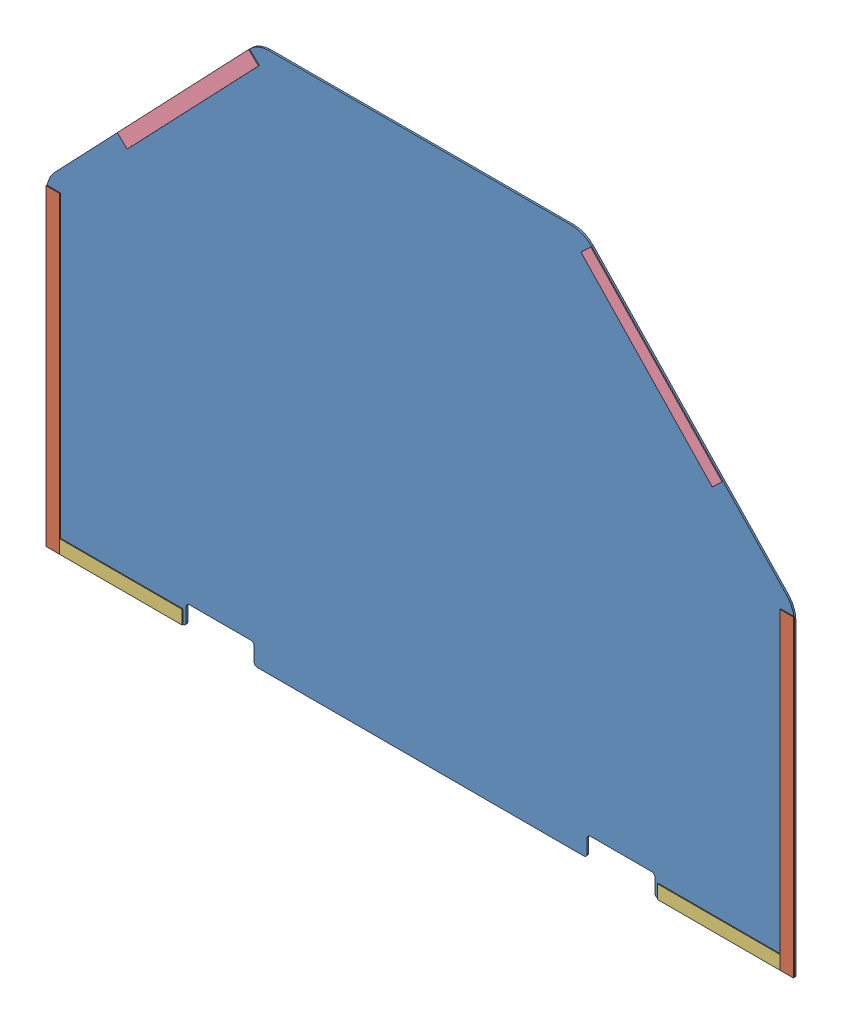
SolidWorks assembly GE-19081, configuration GE-19081-red. Lengths in mm.
Overall size (1397 1009.65 4.76).
7 component instances, 4 part files, 9 mates.
Components (placement in the parent):
- GE-19081-1: GE-19081 [GE-19081] at origin
- Loop_1_23-1: Loop_1_23 [Default] at (-685.8 292.1 4.7625) x (0 -1 0) z (0 0 -1)
- Loop_1_9-1: Loop_1_9 [Default] at (-673.1 0 3.175) x (1 0 0) z (0 -1 0)
- Loop_1_23-2: Loop_1_23 [Default] at (685.8 292.1 3.175) x (0 -1 0) z (0 0 1)
- Loop_1_9-2: Loop_1_9 [Default] at (673.1 25.4 3.175) x (-1 0 0) z (0 1 0)
- Loop_1_14-2: Loop_1_14 [Default] at (-565.25 736.5976 4.7625) x (0.690211 0.723608 0) z (-0.723608 0.690211 0)
- Loop_1_14-3: Loop_1_14 [Default] at (546.8703 719.0663 4.7625) x (-0.690211 0.723608 0) z (-0.723608 -0.690211 0)
Mates (geometry in assembly coordinates):
- Coincident1: coincident: plane of GE-19081-1 through (0 0 3.175) normal (0 0 1); plane of Loop_1_23-1 through (-685.8 292.1 3.175) normal (0 0 -1)
- Coincident2: coincident: plane of GE-19081-1 through (-698.5 596.9 3.175) normal (-1 0 0); plane of Loop_1_23-1 through (-698.5 584.2 3.175) normal (-1 0 0)
- Coincident3: coincident: plane of GE-19081-1 through (-698.5 0 3.175) normal (0 -1 0); plane of Loop_1_23-1 through (-698.5 0 3.175) normal (0 -1 0)
- Coincident4: coincident: plane of GE-19081-1 through (0 0 3.175) normal (0 0 1); plane of Loop_1_9-1 through (-673.1 0 3.175) normal (0 0 -1)
- Coincident5: coincident: plane of GE-19081-1 through (-698.5 0 3.175) normal (0 -1 0); plane of Loop_1_9-1 through (-673.1 0 4.7625) normal (0 -1 0)
- Coincident6: coincident: plane of assembly; plane of assembly; plane of Loop_1_23-1 through (-673.1 584.2 3.175) normal (1 0 0); plane of Loop_1_9-1 through (-673.1 0 4.7625) normal (-1 0 0)
- Coincident10: coincident: plane of GE-19081-1 through (0 0 3.175) normal (0 0 1); plane of Loop_1_14-2 through (-565.25 736.5976 3.175) normal (0 0 -1)
- Coincident11: coincident: plane of GE-19081-1 through (-304.8 1009.65 3.175) normal (-0.723608 0.690211 0); plane of Loop_1_14-2 through (-565.25 736.5976 3.175) normal (-0.723608 0.690211 0)
- Coincident14: coincident: point of GE-19081-1; line of Loop_1_14-2 through (-319.8109 993.9127 3.175) axis (0 0 1)
